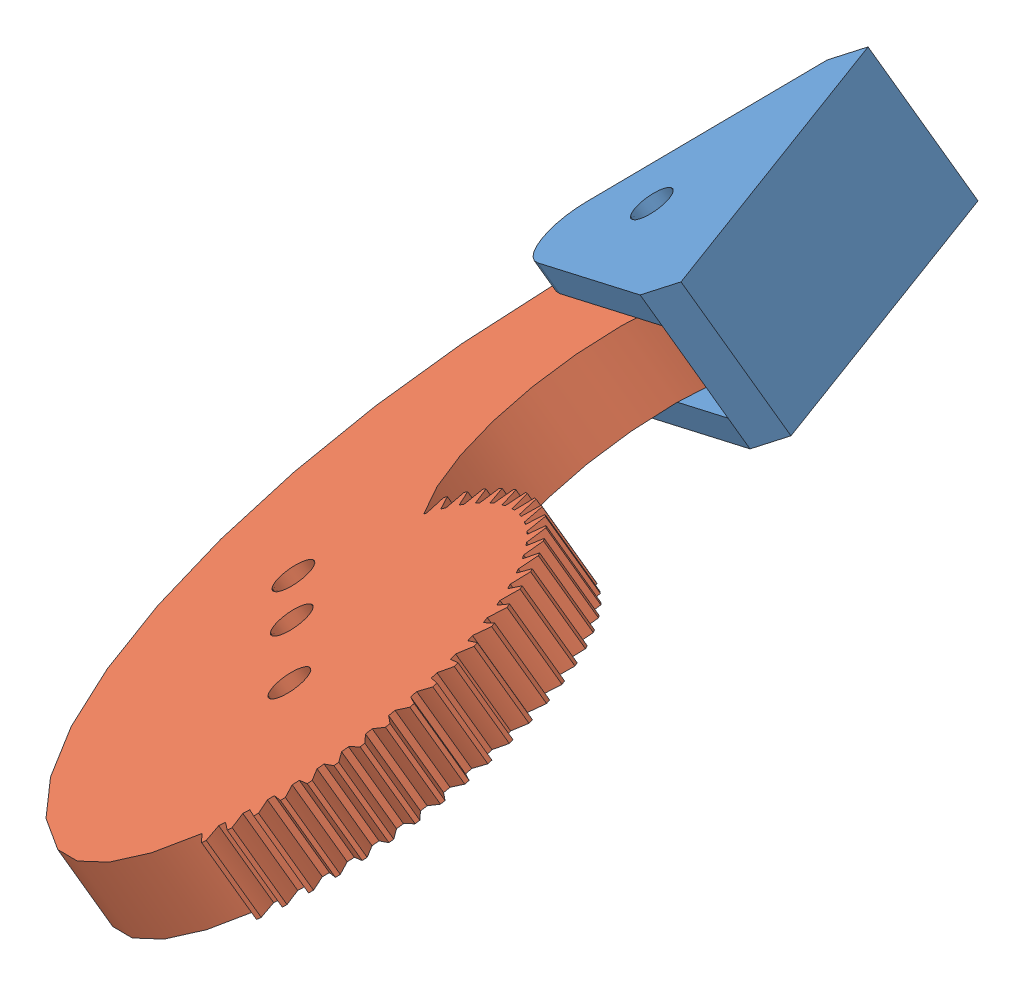
SolidWorks assembly Złożenie6, configuration Domyślna. Lengths in mm.
Overall size (46 32 64.72).
2 component instances, 2 part files, 3 mates.
Components (placement in the parent):
- Chwyt-1: Chwyt [Domyślna] at (88.6962 -174.049 17.2042) x (0.795979 0.579475 -0.175003) z (0.533395 -0.808131 -0.249828) size (17.08 20 10)
- koło_zębate-1: koło_zębate [ISO - Spur gear 1M 30T 20PA 6FW ---S30A75H50L5.0N] at (91.8364 -192.3197 50.9877) x (-0.533395 0.808131 0.249828) z (-0.795979 -0.579475 0.175003) size (5 55.03 34.65)
Mates (geometry in assembly coordinates):
- Koncentryczne110: concentric anti-aligned: cylinder of koło_zębate-1 through (83.1325 -181.6887 18.0298) axis (-0.533395 0.808131 0.249828) radius 1.3; cylinder of Chwyt-1 through (86.8663 -187.3456 16.281) axis (0.533395 -0.808131 -0.249828) radius 1.3
- Wspólnie81: coincident anti-aligned: plane of koło_zębate-1 through (91.8364 -192.3197 50.9877) normal (0.533395 -0.808131 -0.249828); plane of Chwyt-1 through (94.1405 -183.5669 27.5939) normal (-0.533395 0.808131 0.249828)
- Równolegle8: parallel anti-aligned: plane of koło_zębate-1 through (57.4101 -132.1497 36.4984) normal (0.795979 0.579475 -0.175003); plane of Chwyt-1 through (86.3082 -175.7875 17.7292) normal (-0.795979 -0.579475 0.175003)
